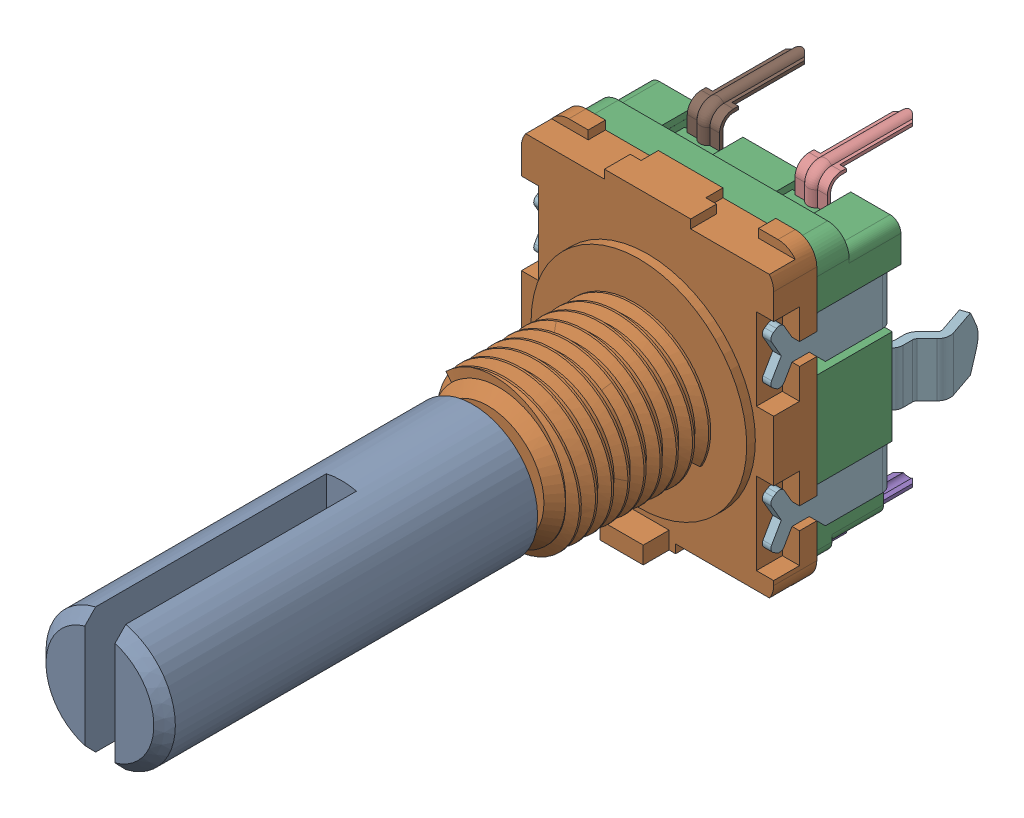
SolidWorks assembly ENC1, configuration Défaut. Lengths in mm.
Overall size (13.1 15.13 35.07).
18 component instances, 7 part files, 0 mates.
Components (placement in the parent):
- Open CASCADE STEP translator 6.8 1.7.1-1: Open CASCADE STEP translator 6.8 1.7.1 [Défaut] at origin size (13.1 15.13 35.07)
  - Body_1-1: Body_1 [Défaut] at (2.5 -6.5 0) x (-1 0 0) z (0 0 1) size (13.1 15.13 35.07)
    - Imported-1: Imported [Défaut] at (0 0 13.6) size (6 6 18)
    - Imported_2-1: Imported_2 [Défaut] at (0 0 3.443) size (11.7 13.8 9.4)
    - Imported_3-1: Imported_3 [Défaut] at (-0.85 -0.6436 6.5892) size (11.7 13.3 3.9)
    - Imported-2: Imported [Défaut] at (0 0 6.6326) size (13.1 14.95 9.45)
      - Imported_2-1: Imported_2 [Défaut] at (-2.5 7.575 -10.2243) x (0 -1 0) z (0 0 1) size (2.34 1.5 6.65)
        - SOLID-1: SOLID [Défaut] at origin size (0.6 1.5 0.15)
        - SOLID_2-1: SOLID_2 [Défaut] at origin size (2.15 1.5 6.65)
      - Imported_2-2: Imported_2 [Défaut] at (0 7.575 -10.2243) x (0 -1 0) z (0 0 1) size (2.34 1.5 6.65)
        - SOLID-1: SOLID [Défaut] at origin size (0.6 1.5 0.15)
        - SOLID_2-1: SOLID_2 [Défaut] at origin size (2.15 1.5 6.65)
      - Imported_2-3: Imported_2 [Défaut] at (2.5 7.575 -10.2243) x (0 -1 0) z (0 0 1) size (2.34 1.5 6.65)
        - SOLID-1: SOLID [Défaut] at origin size (0.6 1.5 0.15)
        - SOLID_2-1: SOLID_2 [Défaut] at origin size (2.15 1.5 6.65)
      - Imported_4-1: Imported_4 [Défaut] at (-2.5 -7.075 -10.2243) x (0 1 0) z (0 0 1) size (2.15 1.5 4.73)
      - Imported_4-2: Imported_4 [Défaut] at (2.5 -7.075 -10.2243) x (0 1 0) z (0 0 1) size (2.15 1.5 4.73)
      - Imported_5-1: Imported_5 [Défaut] at (-24.7094 3.8245 8.4125) size (13.1 9.9 9.18)
